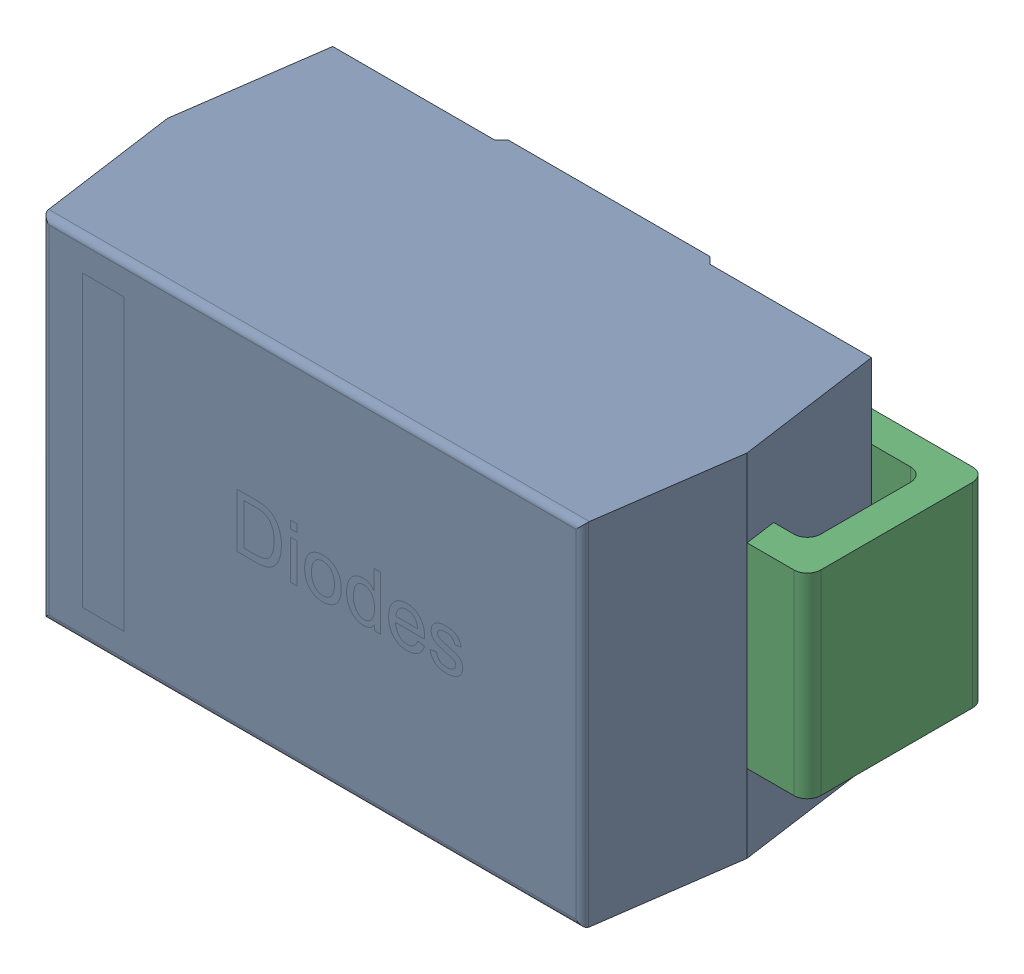
SolidWorks assembly Diode_Diodes_Inc_SMAJ5_0A-13-F_eec, configuration Default. Lengths in mm.
Overall size (5.2 2.61 2.4).
3 component instances, 3 part files, 0 mates.
Components (placement in the parent):
- Diodes Inc. SMAJ5.0A-13-F 1-1: Diodes Inc. SMAJ5.0A-13-F 1 [Default] at (-2.4537 -1.5741 -1.1) size (4.3 2.61 2.2)
- Diodes Inc. SMAJ5.0A-13-F 2-1: Diodes Inc. SMAJ5.0A-13-F 2 [Default] at (-4.8275 -0.8491 -0.6375) x (1 0 0) z (0 -1 0) size (1.14 1.33 1.45)
- Diodes Inc. SMAJ5.0A-13-F 2_MIR-1: Diodes Inc. SMAJ5.0A-13-F 2_MIR [Default] at (-0.08 -0.8491 -0.6375) x (-1 0 0) z (0 1 0) size (1.14 1.33 1.45)
